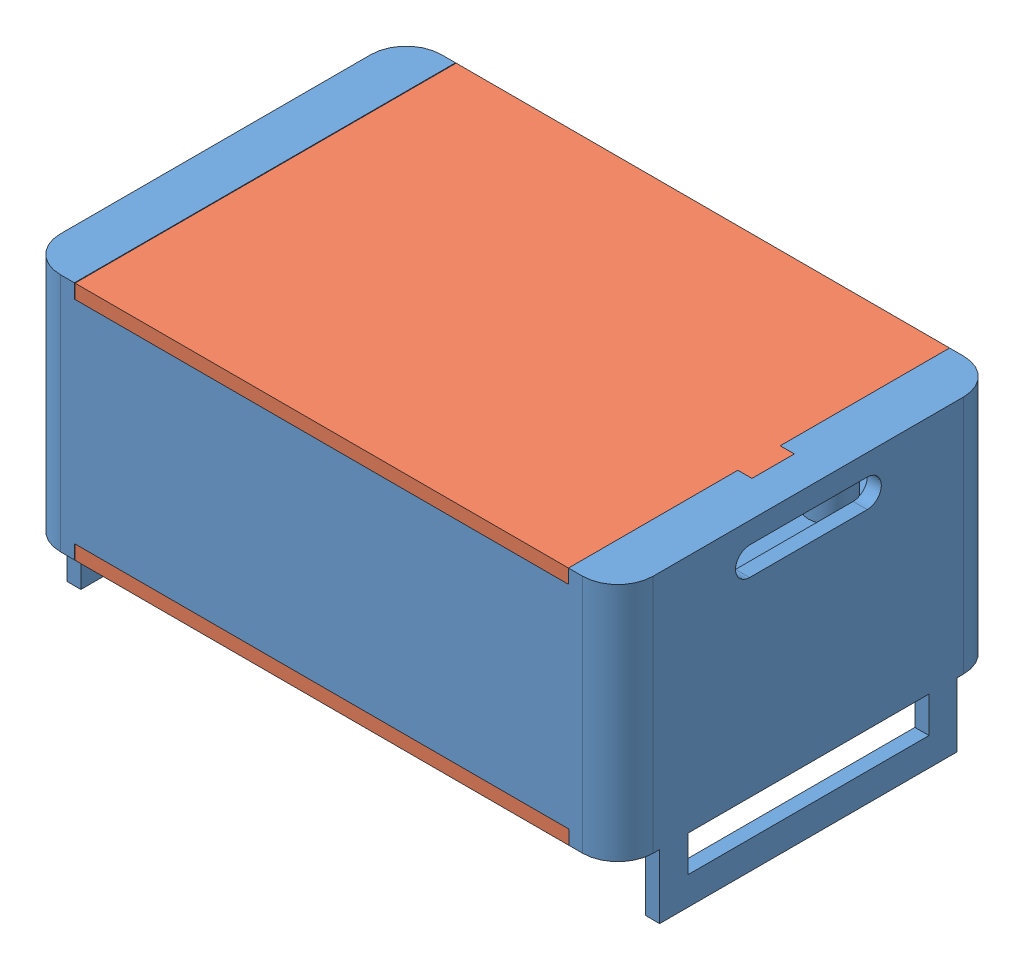
SolidWorks assembly TemporaryMainFrame, configuration Default. Lengths in mm.
Overall size (84 43.1 57.37).
9 component instances, 4 part files, 6 mates.
Components (placement in the parent):
- MainFrame-1: MainFrame [Default] at (31.3798 50.9243 65.9038) size (84 43.1 54)
- MainFrame-Lid-1: MainFrame-Lid [Default] at (31.4677 65.9243 65.9038) size (76.81 5.98 54)
- 4x AAA Alkaline 1.5 V Battery Pack-1: 4x AAA Alkaline 1.5 V Battery Pack [Default] at (28.7918 51.7179 65.5539) x (0 0 1) z (1 0 0) size (54.8 18.32 52.2)
  - BatteryPack4AAA-1: BatteryPack4AAA [Default] at origin size (54.34 16.46 52.2)
  - AAABattery-1: AAABattery [Default] at (17.6964 8.2079 19.2636) x (-0.85083 -0.525441 0) z (0.525441 -0.85083 0) size (10.3 43.83 10.3)
  - AAABattery-2: AAABattery [Default] at (-5.91 8.2079 19.2636) x (-0.85083 -0.525441 0) z (0.525441 -0.85083 0) size (10.3 43.83 10.3)
  - AAABattery-3: AAABattery [Default] at (-17.6921 8.2079 -19.302) x (0.85083 -0.525441 0) z (-0.525441 -0.85083 0) size (10.3 43.83 10.3)
  - AAABattery-4: AAABattery [Default] at (5.955 8.2079 -19.4197) x (0.85083 -0.525441 0) z (-0.525441 -0.85083 0) size (10.3 43.83 10.3)
- MainFrame-Lid-2: MainFrame-Lid [Default] at (31.4714 35.9243 65.9038) x (1 0 0) z (0 0 -1) size (76.81 5.98 54)
Mates (geometry in assembly coordinates):
- Coincident1: coincident aligned: plane of MainFrame-1 through (31.3798 67.9243 65.9038) normal (0 1 0); plane of MainFrame-Lid-1 through (31.4677 67.9243 65.9038) normal (0 1 0)
- Coincident3: coincident aligned: plane of MainFrame-1 through (-5.6202 35.9243 92.9038) normal (0 0 1); plane of MainFrame-Lid-1 through (-3.5323 67.9243 92.9038) normal (0 0 1)
- Coincident4: coincident anti-aligned: plane of MainFrame-1 through (-5.6202 50.9243 87.9038) normal (0 -1 0); plane of 4x AAA Alkaline 1.5 V Battery Pack-1/BatteryPack4AAA-1 through (28.7951 50.9243 65.5375) normal (0 1 0)
- Parallel1: parallel anti-aligned: plane of MainFrame-1 through (-5.6202 35.9243 90.9038) normal (0 0 -1); plane of 4x AAA Alkaline 1.5 V Battery Pack-1/BatteryPack4AAA-1 through (2.6951 46.1843 89.8735) normal (0 0 1)
- Coincident6: coincident aligned: plane of MainFrame-1 through (-5.6202 33.9243 87.9038) normal (0 -1 0); plane of MainFrame-Lid-2 through (31.4714 33.9243 65.9038) normal (0 -1 0)
- Coincident7: coincident aligned: plane of MainFrame-1 through (-5.6202 35.9243 38.9038) normal (0 0 -1); plane of MainFrame-Lid-2 through (-3.5286 33.9243 38.9038) normal (0 0 -1)
